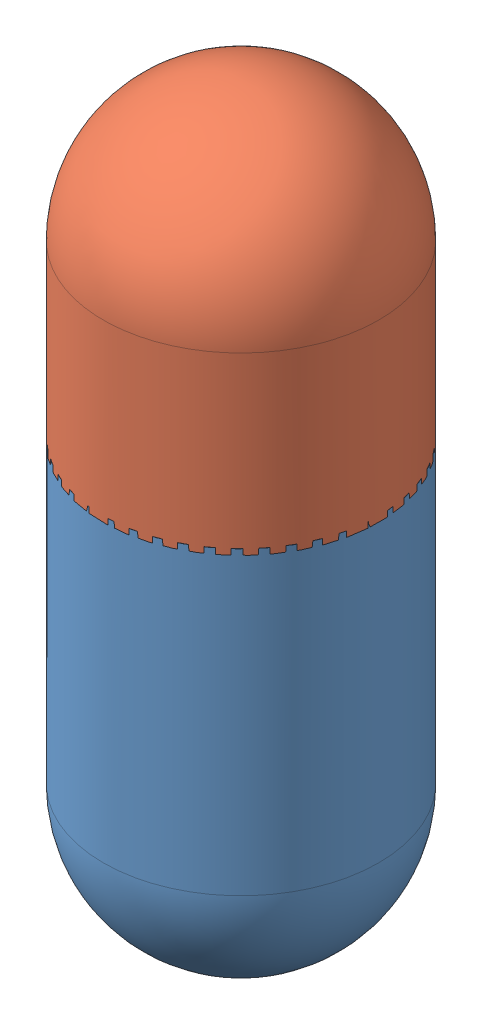
SolidWorks assembly SuctionBasicAssembly, configuration Default. Lengths in mm.
Overall size (178.38 378.14 178.38).
2 component instances, 2 part files, 1 mates.
Components (placement in the parent):
- BottomSuction-1: BottomSuction [Default] at (-11.6123 49.8644 282.1723) size (139.7 234.95 139.7)
- TopSuction-1: TopSuction [Default] at (-11.6123 212.1041 282.1723) x (0.334496 0 -0.942397) z (0.942397 0 0.334496) size (139.7 158.75 139.7)
Mates (geometry in assembly coordinates):
- Concentric6: concentric aligned: cylinder of BottomSuction-1 through (-11.6123 -13.6356 282.1723) axis (0 1 0) radius 69.85; cylinder of TopSuction-1 through (-11.6123 358.1541 282.1723) axis (0 1 0) radius 69.85
